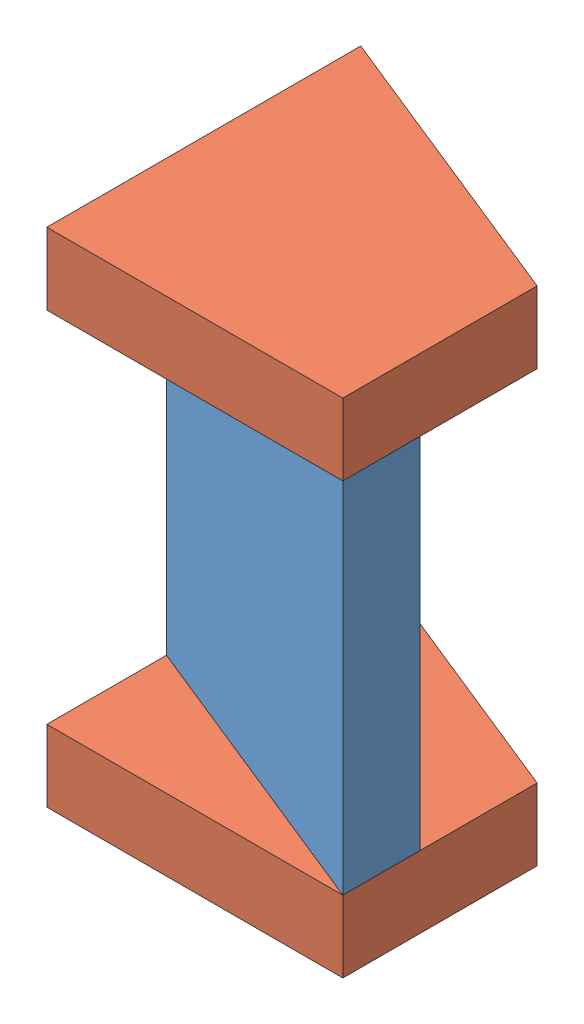
SolidWorks assembly food slider assembly, configuration Default. Lengths in mm.
Overall size (46.3 56 35).
3 component instances, 2 part files, 6 mates.
Components (placement in the parent):
- food slider-1: food slider [Default] at (-11.7626 3.9692 41.5351) size (33 40 21.96)
- food slider side-1: food slider side [Default] at (-11.7626 43.9692 28.4962) size (46.3 8 35)
- food slider side-2: food slider side [Default] at (-11.7626 -4.0308 28.4962) size (46.3 8 35)
Mates (geometry in assembly coordinates):
- Coincident3: coincident anti-aligned: plane of food slider-1 through (-11.7626 43.9692 41.5351) normal (0 1 0); plane of food slider side-1 through (-11.7626 43.9692 28.4962) normal (0 -1 0)
- Coincident11: coincident anti-aligned: plane of food slider-1 through (-11.7626 3.9692 41.5351) normal (0 -1 0); plane of food slider side-2 through (-11.7626 3.9692 28.4962) normal (0 1 0)
- Coincident14: coincident aligned: plane of food slider-1 through (21.2374 43.9692 19.8679) normal (1 0 0); plane of food slider side-2 through (21.2374 3.9692 28.4962) normal (1 0 0)
- Coincident15: coincident aligned: line of food slider-1 through (21.2374 43.9692 28.4962) axis (0 -1 0); line of food slider side-2 through (21.2374 3.9692 28.4962) axis (0 -1 0)
- Coincident16: coincident aligned: plane of food slider-1 through (21.2374 43.9692 19.8679) normal (1 0 0); plane of food slider side-1 through (21.2374 51.9692 28.4962) normal (1 0 0)
- Coincident17: coincident aligned: line of food slider-1 through (21.2374 43.9692 28.4962) axis (0 -1 0); line of food slider side-1 through (21.2374 51.9692 28.4962) axis (0 -1 0)
